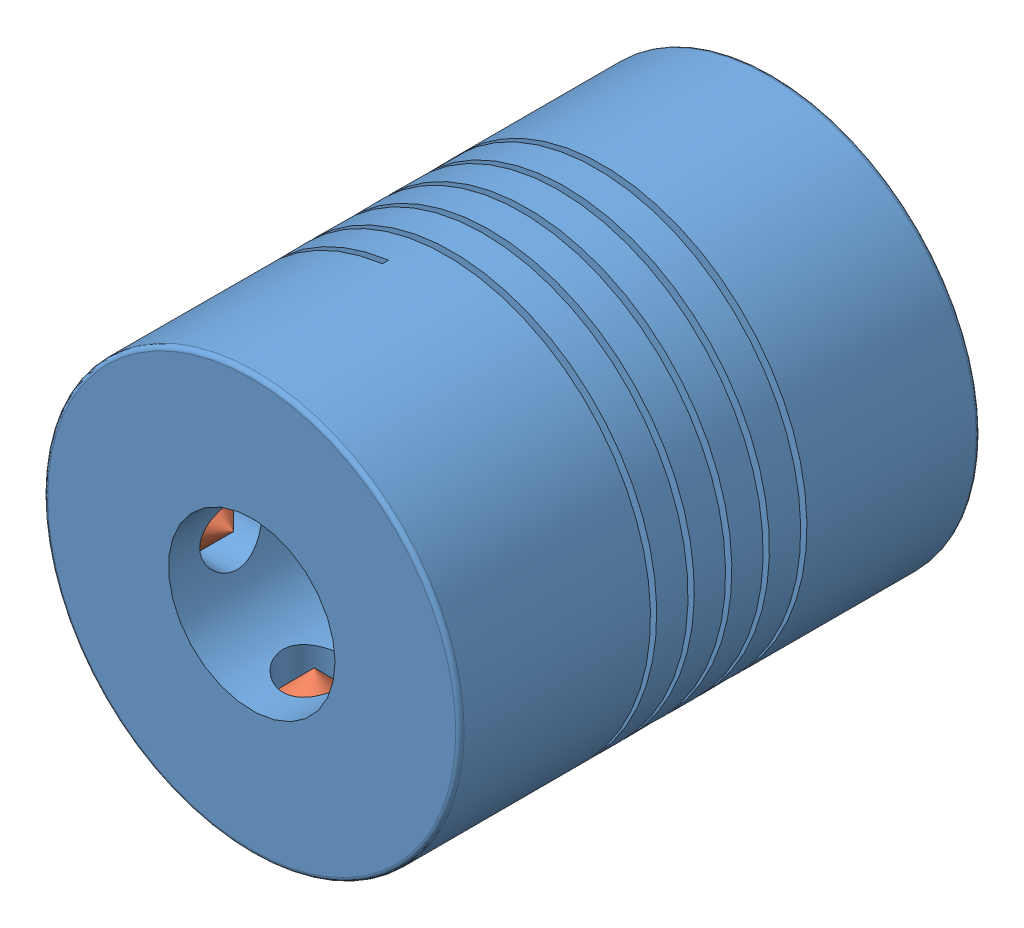
SolidWorks assembly Flexible Shaft Coupler, configuration Predeterminado. Lengths in mm.
Overall size (20.77 20.77 25).
5 component instances, 2 part files, 4 mates.
Components (placement in the parent):
- Flexible Shaft Coupler Body-1: Flexible Shaft Coupler Body [Predeterminado] at (-1.3837 -0.8648 0) size (20.77 20.77 25)
- socket set screw cone point_am-7: socket set screw cone point_am [B18.3.6M - M3 x 0.5 x 6 Hex Socket Cone Pt. SS --N] at (-11.2647 -0.8648 22) x (1 0 0) z (0 -0.164849 0.986319) size (6 3 3)
- socket set screw cone point_am-8: socket set screw cone point_am [B18.3.6M - M3 x 0.5 x 6 Hex Socket Cone Pt. SS --N] at (-11.1909 -0.8648 3) x (1 0 0) z (0 0.00677 0.999977) size (6 3 3)
- socket set screw cone point_am-9: socket set screw cone point_am [B18.3.6M - M3 x 0.5 x 6 Hex Socket Cone Pt. SS --N] at (-1.3837 -10.7654 3) x (0 1 0) z (-0.345086 0 0.938571) size (6 3 3)
- socket set screw cone point_am-10: socket set screw cone point_am [B18.3.6M - M3 x 0.5 x 6 Hex Socket Cone Pt. SS --N] at (-1.3837 -10.5992 22) x (0 1 0) z (-0.865685 0 0.500588) size (6 3 3)
Mates (geometry in assembly coordinates):
- Concéntrica7: concentric anti-aligned: cylinder of Flexible Shaft Coupler Body-1 through (-161.3837 -0.8648 22) axis (1 0 0) radius 1.5; cylinder of socket set screw cone point_am-7 through (-23.9647 -0.8648 22) axis (-1 0 0) radius 1.5
- Concéntrica8: concentric anti-aligned: cylinder of Flexible Shaft Coupler Body-1 through (-161.3837 -0.8648 3) axis (1 0 0) radius 1.5; cylinder of socket set screw cone point_am-8 through (-23.8909 -0.8648 3) axis (-1 0 0) radius 1.5
- Concéntrica10: concentric anti-aligned: cylinder of Flexible Shaft Coupler Body-1 through (-1.3837 -18.8648 3) axis (0 1 0) radius 1.5; cylinder of socket set screw cone point_am-9 through (-1.3837 -23.4654 3) axis (0 -1 0) radius 1.5
- Concéntrica11: concentric anti-aligned: cylinder of Flexible Shaft Coupler Body-1 through (-1.3837 -18.8648 22) axis (0 1 0) radius 1.5; cylinder of socket set screw cone point_am-10 through (-1.3837 -23.2992 22) axis (0 -1 0) radius 1.5
